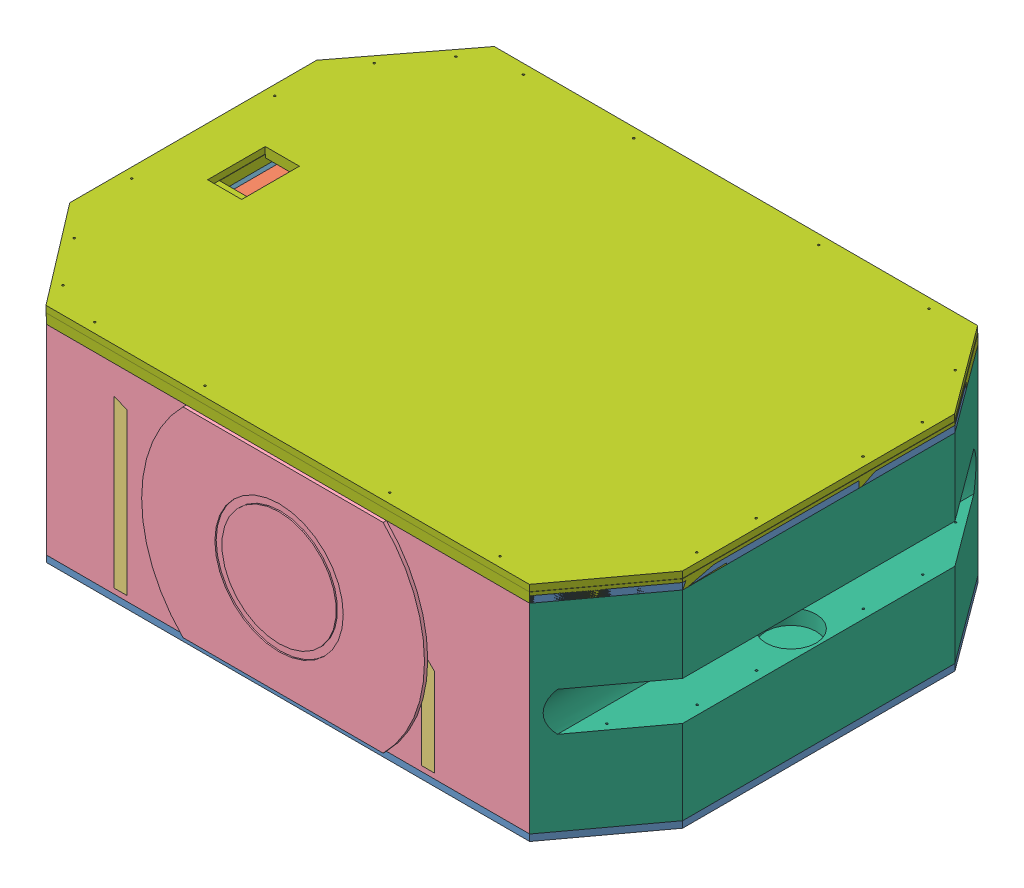
SolidWorks assembly Assembly, configuration Default. Lengths in mm.
Overall size (964.27 343 700.98).
27 component instances, 14 part files, 60 mates.
Components (placement in the parent):
- chasis-1: chasis [Default] at (-186.9242 609.2466 954.3326) size (963.71 10 690.98)
- plate-1: plate [Default] at (-189.3962 839.7327 949.3326) size (953.71 55 680.98)
- bar-1: bar [Default] at (-176.9242 619.2466 954.4328) size (25 308 60)
- bar-2: bar [Default] at (517.0971 619.2466 618.8449) x (0 0 1) z (-1 0 0) size (25 308 60)
- bar-4: bar [Default] at (519.6255 619.2466 1289.8203) x (0 0 -1) z (1 0 0) size (25 308 60)
- jetson_case-1: jetson_case [Default] at (345.5928 849.7327 936.0298) size (103 35 90) (hidden)
- side_1-2: side_1 [Default] at (-186.9242 927.2466 263.3572) x (1 0 0) z (0 -1 0) size (745 30 308)
- side_1-3: side_1 [Default] at (-186.9242 619.2466 1645.3081) x (1 0 0) z (0 1 0) size (745 30 308)
- back side-1: back side [Default] at (-186.9242 619.2466 954.3326) x (1 0 0) z (0 1 0) size (118.58 690.98 308)
- Front side-2: Front side [Default] at (-186.9242 619.2466 954.3326) x (1 0 0) z (0 -1 0) size (100.13 690.98 308)
- bottom plate_1-1: bottom plate_1 [Default] at (-186.9242 927.2466 1645.3081) x (1 0 0) z (0 1 0) size (963.71 690.98 15)
- Motor_Hanger-1: Motor_Hanger [Default] at (259.3628 619.2466 1100.2382) size (98.3 65.3 120) (hidden)
- Motor_Hanger-2: Motor_Hanger [Default] at (254.1785 619.2466 835.9902) size (98.3 65.3 120) (hidden)
- bar-5: bar [Default] at (45.0762 619.2466 618.8449) x (0 0 1) z (-1 0 0) size (25 308 60)
- bar-6: bar [Default] at (45.8603 619.2466 1289.8203) x (0 0 -1) z (1 0 0) size (25 308 60)
- chasis-2: chasis [Default] at (-186.9242 927.2466 954.3326) size (963.71 10 690.98)
- bottom plate_1-2: bottom plate_1 [Default] at (-187.4865 952.2466 263.3572) x (1 0 0) z (0 -1 0) size (963.71 690.98 15)
- bottom plate_final^Assembly-1: bottom plate_final^Assembly [Default] at (-186.9242 609.2466 954.3326) x (-1 0 0) z (0 -1 0) size (963.71 690.98 2) (hidden, virtual)
- caster bar_V-4: caster bar_V [Default] at (-3.106 619.2466 883.0876) x (0 0 1) z (-1 0 0) size (142.49 67.1 19.05)
- caster bar_V-5: caster bar_V [Default] at (590.6167 619.2466 883.0876) x (0 0 1) z (-1 0 0) size (142.49 67.1 19.05)
- motor_brackect-4: motor_brackect [Default] at (80.9291 619.2466 1125.5776) size (138.1 81.05 19.05)
- horisontal bar-1: horisontal bar [Default] at (34.0342 838.8257 627.8203) x (1 0 0) z (0 -1 0) size (19.05 647 19.05)
- horisontal bar-2: horisontal bar [Default] at (512.8396 840.1206 627.8203) x (1 0 0) z (0 -1 0) size (19.05 647 19.05)
- caster bar_V-6: caster bar_V [Default] at (-63.3243 619.2466 883.0876) x (0 0 1) z (-1 0 0) size (142.49 67.1 19.05)
- caster bar_V-7: caster bar_V [Default] at (656.8071 619.2466 883.0876) x (0 0 1) z (-1 0 0) size (142.49 67.1 19.05)
- motor_brackect-5: motor_brackect [Default] at (22.8513 619.2466 764.0376) size (138.1 81.05 19.05)
- midlle_plate_horisontal-1: midlle_plate_horisontal [Default] at (284.1542 819.7757 965.5293) size (462.14 19.05 19.05)
Mates (geometry in assembly coordinates):
- Parallel1: parallel aligned: plane of chasis-1 through (-186.9242 619.2466 954.3326) normal (0 1 0); plane of plate-1 through (-189.3962 849.7327 949.3326) normal (0 1 0)
- Coincident14: coincident anti-aligned: plane of chasis-1 through (-186.9242 619.2466 954.3326) normal (0 1 0); plane of bar-1 through (-186.9242 619.2466 983.4328) normal (0 -1 0)
- Coincident15: coincident aligned: plane of chasis-1 through (-186.9242 619.2466 764.0376) normal (-1 0 0); plane of bar-1 through (-186.9242 619.2466 954.4328) normal (-1 0 0)
- Coincident17: coincident anti-aligned: plane of chasis-1 through (-186.9242 619.2466 954.3326) normal (0 1 0); plane of bar-4 through (548.6255 619.2466 1299.8203) normal (0 -1 0)
- Coincident18: coincident anti-aligned: plane of chasis-1 through (-186.9242 619.2466 954.3326) normal (0 1 0); plane of bar-2 through (488.0971 619.2466 608.8449) normal (0 -1 0)
- Coincident24: coincident: line of chasis-1 through (-68.3442 619.2466 1299.8203) axis (1 0 0); plane of bar-4 through (519.6255 619.2466 1299.8203) normal (0 0 1)
- Coincident29: coincident aligned: plane of chasis-1 through (-68.3442 619.2466 608.8449) normal (0 0 -1); plane of bar-2 through (517.0971 619.2466 608.8449) normal (0 0 -1)
- Coincident44: coincident anti-aligned: plane of chasis-1 through (-186.9242 619.2466 954.3326) normal (0 1 0); plane of side_1-2 through (676.6558 619.2466 608.8449) normal (0 -1 0)
- Coincident45: coincident anti-aligned: line of side_1-2 through (-68.3442 619.2466 608.8449) axis (1 0 0)
- Coincident46: coincident aligned: line of chasis-1 through (676.6558 619.2466 608.8449) axis (0 -1 0); line of side_1-2 through (676.6558 927.2466 608.8449) axis (0 -1 0)
- Coincident50: coincident anti-aligned: plane of chasis-1 through (-186.9242 619.2466 954.3326) normal (0 1 0); plane of side_1-3 through (676.6558 619.2466 1299.8203) normal (0 -1 0)
- Coincident51: coincident anti-aligned: line of side_1-3 through (676.6558 619.2466 1299.8203) axis (-1 0 0)
- Coincident52: coincident anti-aligned: line of chasis-1 through (-68.3442 619.2466 1299.8203) axis (0 -1 0); line of side_1-3 through (-68.3442 619.2466 1299.8203) axis (0 1 0)
- InPlace2: in place: plane of chasis-1 through (-186.9242 619.2466 954.3326) normal (0 1 0); plane of ? through (0 619.2466 0) normal (0 1 0); moOrthogonalPlaneRef_w of chasis-1 through (-186.9242 619.2466 954.3326) normal (0 1 0); plane of ? through (0 619.2466 0) normal (0 0 -1); plane of chasis-1 through (-186.9242 619.2466 954.3326) normal (0 1 0); plane of ? through (0 619.2466 0) normal (1 0 0); plane of chasis-1 through (-186.9242 619.2466 954.3326) normal (0 1 0); unknown of back side-1
- Coincident53: coincident aligned: plane of chasis-1; plane of back side-1
- Coincident54: coincident aligned: moOrthogonalPlaneRef_w of chasis-1 through (-186.9242 619.2466 954.3326) normal (0 0 -1); plane of Part2^Assembly-1 through (-186.9242 619.2466 954.3326) normal (0 0 -1)
- Coincident55: coincident anti-aligned: moOrthogonalPlaneRef_w of chasis-1 through (-186.9242 619.2466 954.3326) normal (-1 0 0); plane of Part2^Assembly-1 through (-186.9242 619.2466 954.3326) normal (1 0 0)
- Coincident60: coincident aligned: line of chasis-1 through (776.7858 619.2466 744.5037) axis (0 -1 0); line of Front side-2 through (776.7858 749.1541 744.5037) axis (0 -1 0)
- Coincident61: coincident aligned: plane of plate-1 through (671.6598 919.7327 608.8449) normal (0 0 -1); plane of side_1-2 through (676.6558 927.2466 608.8449) normal (0 0 -1)
- Coincident62: coincident aligned: plane of plate-1 through (-68.3442 919.7327 608.8449) normal (-0.794597 0 -0.607137); plane of back side-1 through (-68.3442 1628.3231 608.8449) normal (-0.794597 0 -0.607137)
- Coincident64: coincident: point of chasis-1; line of Front side-2 through (776.7858 749.1541 1164.1615) axis (0 -1 0)
- Coincident65: coincident anti-aligned: line of chasis-1 through (776.7858 619.2466 1164.1615) axis (0 0 -1); line of Front side-2 through (776.7858 619.2466 744.5037) axis (0 0 1)
- InPlace3: in place: plane of side_1-3 through (676.6558 927.2466 1299.8203) normal (0 1 0); plane of ? through (0 927.2466 0) normal (0 1 0); plane of side_1-3 through (676.6558 927.2466 1299.8203) normal (0 1 0); plane of ? through (0 927.2466 0) normal (0 0 -1); plane of side_1-3 through (676.6558 927.2466 1299.8203) normal (0 1 0); plane of ? through (0 927.2466 0) normal (1 0 0); plane of side_1-3 through (676.6558 927.2466 1299.8203) normal (0 1 0); unknown of bottom plate_1-1
- Coincident66: coincident aligned: plane of side_1-3; plane of bottom plate_1-1
- Coincident67: coincident aligned: moOrthogonalPlaneRef_w of side_1-3 through (-186.9242 927.2466 1645.3081) normal (0 0 -1); plane of bottom plate_1-1 through (-186.9242 927.2466 1645.3081) normal (0 0 -1)
- Coincident68: coincident anti-aligned: moOrthogonalPlaneRef_w of side_1-3 through (-186.9242 927.2466 1645.3081) normal (-1 0 0); plane of bottom plate_1-1 through (-186.9242 927.2466 1645.3081) normal (1 0 0)
- Coincident66: coincident anti-aligned: plane of plate-1 through (-189.3962 849.7327 949.3326) normal (0 1 0); plane of jetson_case-1 through (345.5928 849.7327 936.0298) normal (0 -1 0)
- Coincident70: coincident anti-aligned: plane of chasis-1 through (-186.9242 619.2466 954.3326) normal (0 1 0); plane of Motor_Hanger-1 through (225.2128 619.2466 1040.2382) normal (0 -1 0)
- Coincident71: coincident anti-aligned: plane of chasis-1 through (-186.9242 619.2466 954.3326) normal (0 1 0); plane of Motor_Hanger-2 through (220.0285 619.2466 775.9902) normal (0 -1 0)
- Coincident73: coincident anti-aligned: plane of chasis-1 through (-186.9242 619.2466 954.3326) normal (0 1 0); plane of bar-6 through (74.8603 619.2466 1299.8203) normal (0 -1 0)
- Coincident74: coincident anti-aligned: plane of chasis-1 through (-186.9242 619.2466 954.3326) normal (0 1 0); plane of bar-5 through (16.0762 619.2466 608.8449) normal (0 -1 0)
- Coincident75: coincident anti-aligned: line of bar-6 through (74.8603 619.2466 1299.8203) axis (-1 0 0)
- Coincident76: coincident anti-aligned: line of bar-5 through (16.0762 619.2466 608.8449) axis (1 0 0)
- Coincident77: coincident anti-aligned: plane of bar-2 through (507.0971 927.2466 608.8449) normal (0 1 0); plane of chasis-2 through (-186.9242 927.2466 954.3326) normal (0 -1 0)
- Coincident81: coincident aligned: line of bar-2 through (527.0971 927.2466 608.8449) axis (-1 0 0); line of chasis-2 through (676.6558 927.2466 608.8449) axis (-1 0 0)
- Coincident83: coincident aligned: plane of chasis-1 through (776.7858 619.2466 744.5037) normal (1 0 0); plane of chasis-2 through (776.7858 937.2466 744.5037) normal (1 0 0)
- Coincident84: coincident anti-aligned: plane of chasis-2 through (-186.9242 937.2466 954.3326) normal (0 1 0); plane of bottom plate_1-2 through (-187.4865 937.2466 263.3572) normal (0 -1 0)
- Coincident85: coincident: plane of chasis-2 through (-68.3442 937.2466 608.8449) normal (0 0 -1); line of bottom plate_1-2 through (676.0935 952.2466 608.8449) axis (-1 0 0)
- InPlace4: in place: plane of chasis-1 through (-186.9242 609.2466 954.3326) normal (0 -1 0); plane of ? through (0 609.2466 0) normal (0 -1 0); plane of chasis-1 through (-186.9242 609.2466 954.3326) normal (0 -1 0); plane of ? through (0 609.2466 0) normal (0 0 -1); plane of chasis-1 through (-186.9242 609.2466 954.3326) normal (0 -1 0); plane of ? through (0 609.2466 0) normal (-1 0 0); plane of chasis-1 through (-186.9242 609.2466 954.3326) normal (0 -1 0); unknown of bottom plate_final^Assembly-1
- Coincident86: coincident aligned: plane of chasis-1; plane of bottom plate_final^Assembly-1
- Coincident87: coincident aligned: moOrthogonalPlaneRef_w of chasis-1 through (-186.9242 609.2466 954.3326) normal (0 0 -1); plane of Part1^Assembly-1 through (-186.9242 609.2466 954.3326) normal (0 0 -1)
- Coincident88: coincident anti-aligned: moOrthogonalPlaneRef_w of chasis-1 through (-186.9242 609.2466 954.3326) normal (1 0 0); plane of Part1^Assembly-1 through (-186.9242 609.2466 954.3326) normal (-1 0 0)
- Coincident89: coincident anti-aligned: plane of chasis-1 through (-186.9242 619.2466 954.3326) normal (0 1 0); plane of caster bar_V-4 through (-3.106 619.2466 883.0876) normal (0 -1 0)
- Coincident90: coincident anti-aligned: line of chasis-1 through (-167.8742 619.2466 883.0876) axis (1 0 0); line of caster bar_V-4 through (-3.106 619.2466 883.0876) axis (-1 0 0)
- Coincident91: coincident anti-aligned: plane of chasis-1 through (-186.9242 619.2466 954.3326) normal (0 1 0); plane of caster bar_V-5 through (590.6167 619.2466 883.0876) normal (0 -1 0)
- Coincident92: coincident anti-aligned: line of chasis-1 through (-167.8742 619.2466 883.0876) axis (1 0 0); line of caster bar_V-5 through (590.6167 619.2466 883.0876) axis (-1 0 0)
- Coincident96: coincident anti-aligned: plane of chasis-1 through (-186.9242 619.2466 954.3326) normal (0 1 0); plane of motor_brackect-4 through (80.9291 619.2466 1125.5776) normal (0 -1 0)
- Coincident107: coincident anti-aligned: plane of bar-4 through (519.6255 619.2466 1274.8203) normal (0 0 -1); plane of horisontal bar-2 through (512.8396 840.1206 1274.8203) normal (0 0 1)
- Parallel8: parallel anti-aligned: plane of bar-2 through (517.0971 619.2466 633.8449) normal (0 0 1); plane of horisontal bar-2 through (512.8396 840.1206 627.8203) normal (0 0 -1)
- Coincident109: coincident anti-aligned: plane of bar-6 through (45.8603 619.2466 1274.8203) normal (0 0 -1); plane of horisontal bar-1 through (34.0342 838.8257 1274.8203) normal (0 0 1)
- Parallel9: parallel anti-aligned: plane of bar-5 through (45.0762 619.2466 633.8449) normal (0 0 1); plane of horisontal bar-1 through (34.0342 838.8257 627.8203) normal (0 0 -1)
- Coincident110: coincident anti-aligned: plane of chasis-1 through (-186.9242 619.2466 954.3326) normal (0 1 0); plane of caster bar_V-7 through (656.8071 619.2466 883.0876) normal (0 -1 0)
- Coincident113: coincident anti-aligned: line of chasis-1 through (-167.8742 619.2466 883.0876) axis (1 0 0); line of caster bar_V-7 through (656.8071 619.2466 883.0876) axis (-1 0 0)
- Coincident114: coincident anti-aligned: plane of chasis-1 through (-186.9242 619.2466 954.3326) normal (0 1 0); plane of caster bar_V-6 through (-63.3243 619.2466 883.0876) normal (0 -1 0)
- Coincident115: coincident anti-aligned: line of chasis-1 through (-167.8742 619.2466 883.0876) axis (1 0 0); line of caster bar_V-6 through (-63.3243 619.2466 883.0876) axis (-1 0 0)
- Coincident116: coincident anti-aligned: line of chasis-1 through (-167.8742 619.2466 1125.5776) axis (1 0 0); line of motor_brackect-4 through (219.0291 619.2466 1125.5776) axis (-1 0 0)
- Coincident117: coincident anti-aligned: plane of chasis-1 through (-186.9242 619.2466 954.3326) normal (0 1 0); plane of motor_brackect-5 through (22.8513 619.2466 764.0376) normal (0 -1 0)
- Coincident118: coincident anti-aligned: line of chasis-1 through (-167.8742 619.2466 764.0376) axis (1 0 0); line of motor_brackect-5 through (160.9513 619.2466 764.0376) axis (-1 0 0)
- Coincident119: coincident anti-aligned: plane of horisontal bar-1 through (53.0842 838.8257 1274.8203) normal (1 0 0); plane of midlle_plate_horisontal-1 through (53.0842 838.8257 956.0043) normal (-1 0 0)
- Coincident120: coincident anti-aligned: line of horisontal bar-1 through (53.0842 838.8257 1274.8203) axis (0 0 -1); line of midlle_plate_horisontal-1 through (53.0842 838.8257 956.0043) axis (0 0 1)
